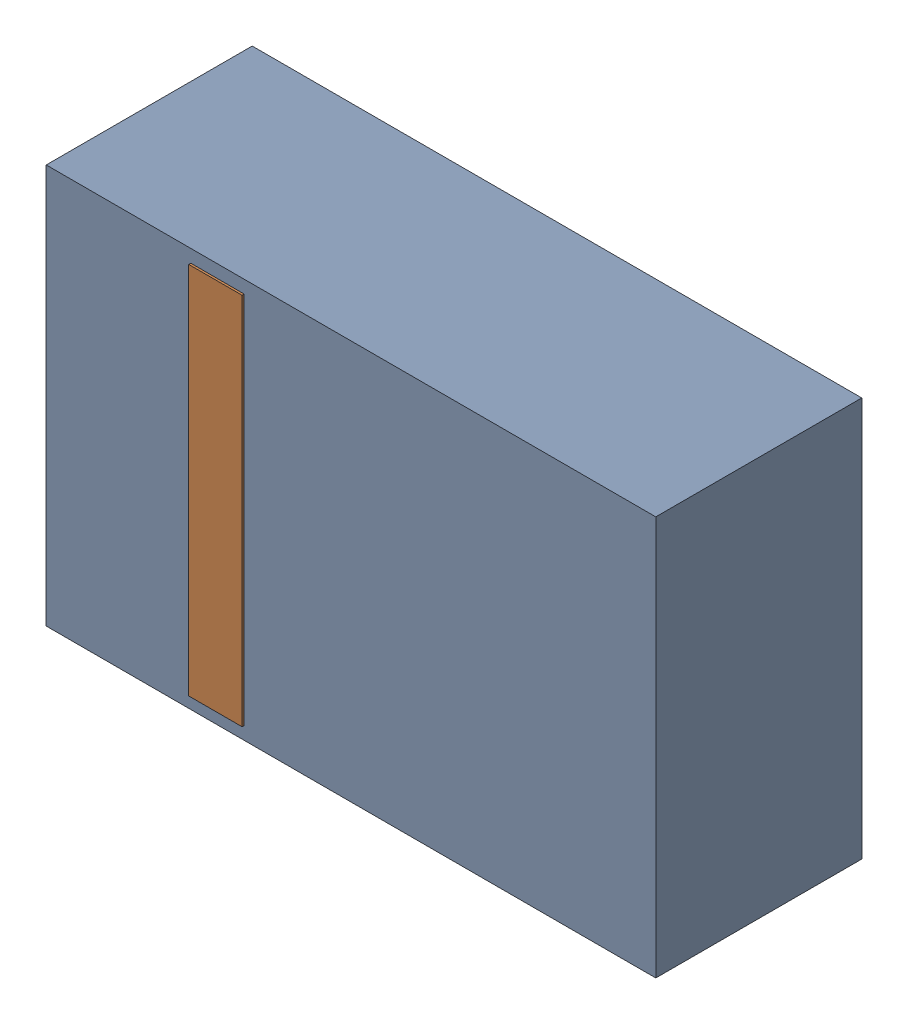
SolidWorks assembly D19, configuration Default. Lengths in mm.
Overall size (2.9 1.9 0.99).
4 component instances, 2 part files, 0 mates.
Components (placement in the parent):
- 905269392-1: 905269392 [Default] at (136.271 61.341 0) size (2.9 1.9 0.98)
  - Extruded_5-1: Extruded_5 [Default] at origin size (2.9 1.9 0.98)
- 905269800-1: 905269800 [Default] at (135.636 61.341 0.95) size (0.25 1.78 0.04)
  - Extruded_6-1: Extruded_6 [Default] at origin size (0.25 1.78 0.04)
